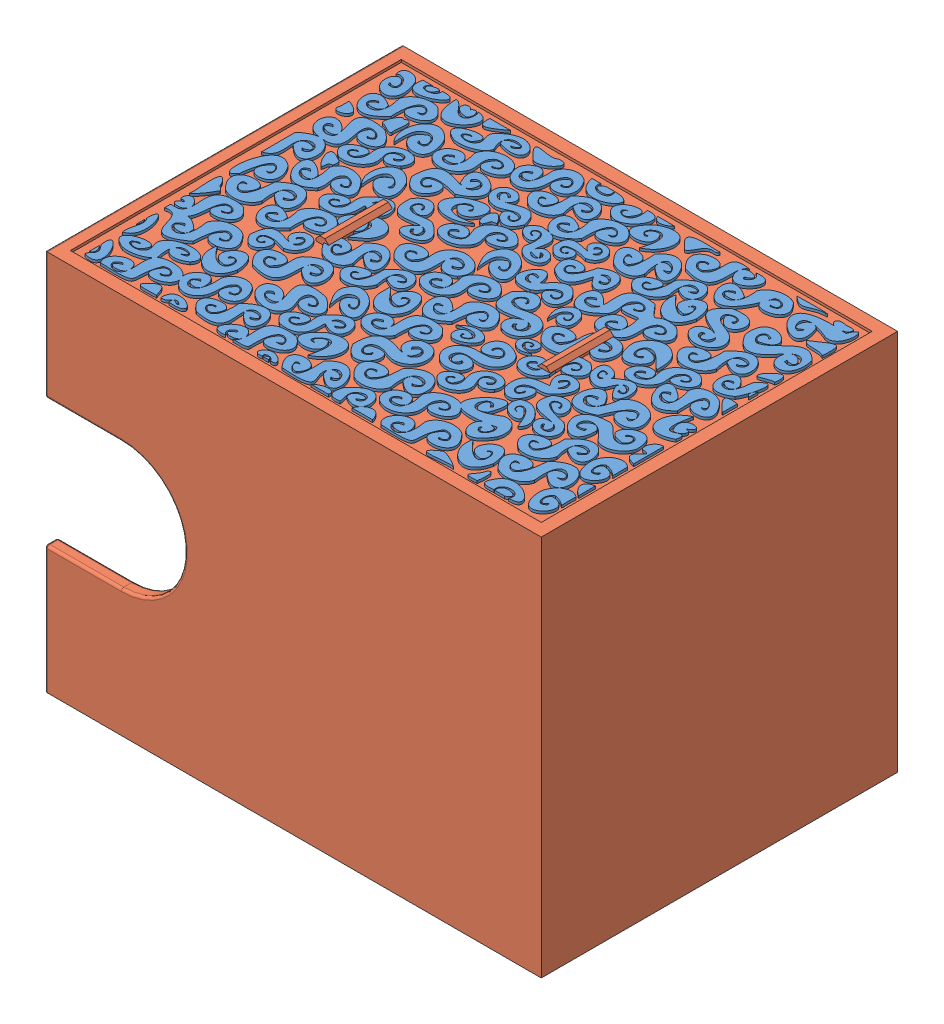
SolidWorks assembly Devil Box, configuration Default. Lengths in mm.
Overall size (99.06 81.28 71.12).
4 component instances, 3 part files, 5 mates.
Components (placement in the parent):
- Box Design - Devil Fruit-1: Box Design - Devil Fruit [Default] at (3.4387 37.2892 97.4489) x (0 0 -1) z (1 0 0) size (65.14 0.51 92.73)
- Box Design - Devil Fruit-2: Box Design - Devil Fruit [Default] at (2.9632 -37.8948 96.6722) x (-0.002751 0 0.999996) z (0.999996 0 0.002751) size (65.14 0.51 92.73)
- Deck Box - B Type-1: Deck Box - B Type [No Drawer] at (48.0977 -11.5067 -22.3855) x (0 1 0) z (0 0 1) size (77.66 99.06 71.12) (hidden)
- Deck Box - A Type-1: Deck Box - A Type [No Drawer] at (48.0977 -11.5067 -24.8989) x (0 1 0) z (0 0 1) size (81.28 99.06 71.12)
Mates (geometry in assembly coordinates):
- Coincident1: coincident anti-aligned: plane of Box Design - Devil Fruit-1 through (3.4387 37.2892 97.4489) normal (0 -1 0); plane of Deck Box - B Type-1 through (48.0977 37.2892 -22.3855) normal (0 1 0)
- Coincident2: coincident anti-aligned: plane of Deck Box - B Type-1 through (48.0977 -37.8948 -22.3855) normal (0 -1 0); plane of Box Design - Devil Fruit-2 through (2.9632 -37.8948 96.6722) normal (0 1 0)
- Coincident4: coincident: plane of Deck Box - B Type-1 through (50.6377 -11.5067 -22.3855) normal (1 0 0); plane of Deck Box - A Type-1 through (50.6377 -11.5067 -24.8989) normal (1 0 0)
- Coincident5: coincident: plane of Deck Box - B Type-1 through (-48.4223 -11.5067 132.4982) normal (0 0 1); plane of Deck Box - A Type-1 through (-48.4223 -11.5067 132.4982) normal (0 0 1)
- Coincident6: coincident aligned: plane of Deck Box - B Type-1 through (-48.4223 -38.4028 -22.3855) normal (0 -1 0); plane of Deck Box - A Type-1 through (-48.4223 -38.4028 -24.8989) normal (0 -1 0)
